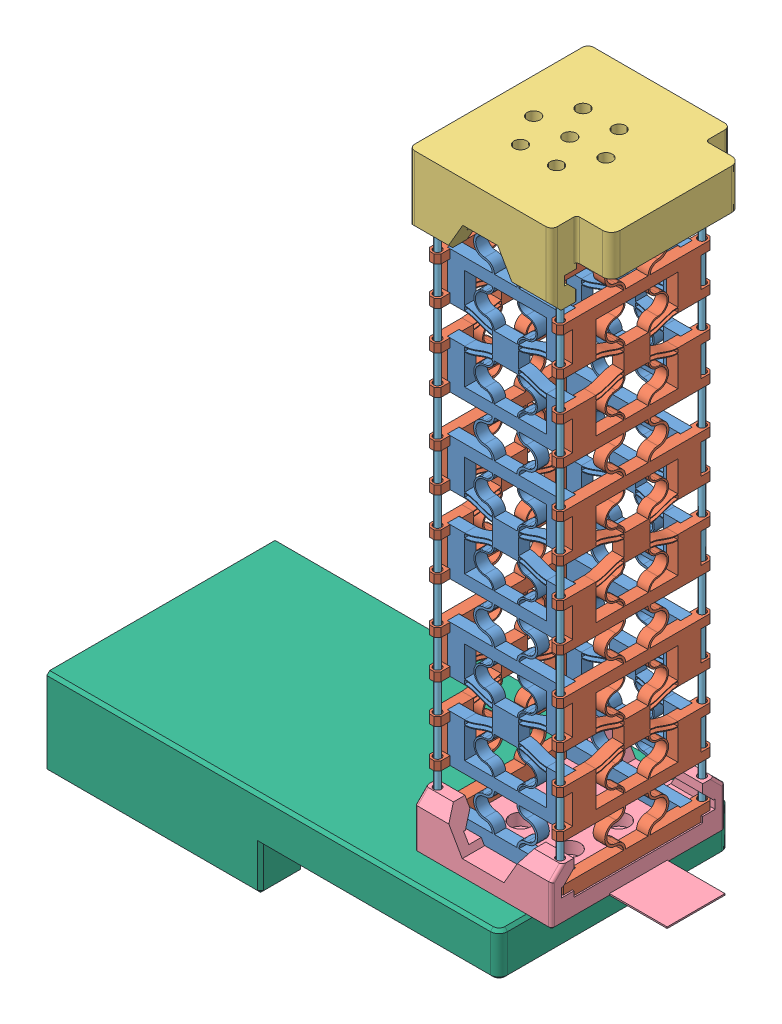
SolidWorks assembly Assem1, configuration Default. Lengths in mm.
Overall size (184.7 240.91 80).
11 component instances, 6 part files, 31 mates.
Components (placement in the parent):
- MM_ver1_of_ROC_ver8_FB-1: MM_ver1_of_ROC_ver8_FB [Default] at origin size (40.4 190.91 4)
- MM_ver1_of_ROC_ver8_LR-1: MM_ver1_of_ROC_ver8_LR [Default] at (-17 0 28.4) x (0 0 -1) z (1 0 0) size (53.1 190.91 4)
- MM_ver1_of_ROC_ver8_FB-2: MM_ver1_of_ROC_ver8_FB [Default] at (0 0 40.4) size (40.4 190.91 4)
- MM_ver1_of_ROC_ver8_LR-3: MM_ver1_of_ROC_ver8_LR [Default] at (29.4 0 16) x (0 0 1) z (-1 0 0) size (53.1 190.91 4)
- podstavek-1: podstavek [Default] at (29.4 57.9704 22.2) x (0 0 1) z (1 0 0) size (62 25.75 61.4)
- pokrov-1: pokrov [Default] at (29.4 -134.9408 22.2) x (0 0 -1) z (1 0 0) size (60 17.75 67.4)
- vodilo-1: vodilo [Default] at (-15 -138.0296 -2.35) x (0.99902 0 -0.044267) z (0.044267 0 0.99902) size (2 200 2)
- vodilo-2: vodilo [Default] at (27.4 -138.0296 -2.35) size (2 200 2)
- vodilo-3: vodilo [Default] at (-15 -138.0296 46.75) size (2 200 2)
- vodilo-4: vodilo [Default] at (27.4 -138.0296 46.75) size (2 200 2)
- drzalo-1: drzalo [Default] at (-86.8 -138.7408 62.2) x (0 -1 0) z (0 0 1) size (30 156.5 80)
Mates (geometry in assembly coordinates):
- Coincident5: coincident aligned: plane of MM_ver1_of_ROC_ver8_FB-1 through (0 56.9704 -40.7082) normal (0 1 0); plane of MM_ver1_of_ROC_ver8_LR-1 through (-61.6806 56.9704 28.4) normal (0 1 0)
- Coincident6: coincident aligned: plane of MM_ver1_of_ROC_ver8_FB-1 through (0 0 0) normal (0 0 -1); plane of MM_ver1_of_ROC_ver8_LR-1 through (-13 34.9704 0) normal (0 0 -1)
- Coincident7: coincident anti-aligned: plane of MM_ver1_of_ROC_ver8_FB-1 through (-14 -128.9408 -40.7082) normal (-1 0 0); plane of MM_ver1_of_ROC_ver8_LR-1 through (-14 56.9704 4.1) normal (1 0 0)
- Coincident8: coincident aligned: plane of MM_ver1_of_ROC_ver8_LR-1 through (-61.6806 56.9704 28.4) normal (0 1 0); plane of MM_ver1_of_ROC_ver8_FB-2 through (0 56.9704 -0.3082) normal (0 1 0)
- Coincident9: coincident aligned: plane of MM_ver1_of_ROC_ver8_LR-1 through (-61.6806 0 44.4) normal (0 0 1); plane of MM_ver1_of_ROC_ver8_FB-2 through (0 0 44.4) normal (0 0 1)
- Coincident14: coincident anti-aligned: plane of MM_ver1_of_ROC_ver8_FB-2 through (26.4 -128.9408 -0.3082) normal (1 0 0); plane of MM_ver1_of_ROC_ver8_LR-3 through (26.4 56.9704 4.1) normal (-1 0 0)
- Coincident15: coincident aligned: plane of MM_ver1_of_ROC_ver8_FB-2 through (-14 -133.9408 -0.3082) normal (0 -1 0); plane of MM_ver1_of_ROC_ver8_LR-3 through (74.0806 -133.9408 0) normal (0 -1 0)
- Coincident16: coincident aligned: plane of MM_ver1_of_ROC_ver8_FB-2 through (0 0 44.4) normal (0 0 1); plane of MM_ver1_of_ROC_ver8_LR-3 through (74.0806 -128.9408 44.4) normal (0 0 1)
- Coincident17: coincident anti-aligned: plane of MM_ver1_of_ROC_ver8_LR-1 through (-14 56.9704 40.3) normal (1 0 0); plane of MM_ver1_of_ROC_ver8_FB-2 through (-14 -128.9408 -0.3082) normal (-1 0 0)
- Coincident18: coincident anti-aligned: plane of MM_ver1_of_ROC_ver8_LR-3 through (74.0806 56.9704 16) normal (0 1 0); plane of podstavek-1 through (-17 56.9704 44.5) normal (0 -1 0)
- Width3: width anti-aligned: plane of MM_ver1_of_ROC_ver8_LR-3 through (29.4 62.8799 16) normal (1 0 0); plane of MM_ver1_of_ROC_ver8_LR-1 through (-17 62.8799 28.4) normal (-1 0 0); plane of podstavek-1 through (-18.5 57.9704 22.2) normal (-1 0 0); plane of podstavek-1 through (30.9 57.9704 22.2) normal (1 0 0)
- Width1: width anti-aligned: plane of MM_ver1_of_ROC_ver8_LR-3 through (74.0806 0 44.4) normal (0 0 1); plane of MM_ver1_of_ROC_ver8_LR-3 through (74.0806 0 0) normal (0 0 -1); plane of podstavek-1 through (-17 53.0204 44.5) normal (0 0 -1); plane of podstavek-1 through (-17 53.0204 -0.1) normal (0 0 1)
- Width4: width anti-aligned: plane of pokrov-1 through (-17.5 -134.9408 22.2) normal (-1 0 0); plane of pokrov-1 through (29.9 -134.9408 22.2) normal (1 0 0); plane of MM_ver1_of_ROC_ver8_LR-3 through (29.4 62.8799 16) normal (1 0 0); plane of MM_ver1_of_ROC_ver8_LR-1 through (-17 62.8799 28.4) normal (-1 0 0)
- Coincident22: coincident anti-aligned: plane of MM_ver1_of_ROC_ver8_LR-1 through (-61.6806 -133.9408 44.4) normal (0 -1 0); plane of pokrov-1 through (-17 -133.9408 -0.1) normal (0 1 0)
- Width2: width anti-aligned: plane of MM_ver1_of_ROC_ver8_FB-1 through (0 0 0) normal (0 0 -1); plane of MM_ver1_of_ROC_ver8_FB-2 through (0 0 44.4) normal (0 0 1); plane of pokrov-1 through (-17 -129.9908 -0.1) normal (0 0 1); plane of pokrov-1 through (-17 -129.9908 44.5) normal (0 0 -1)
- Coincident23: coincident anti-aligned: plane of podstavek-1 through (-17 61.9704 44.5) normal (0 -1 0); plane of vodilo-1 through (-15 61.9704 -2.35) normal (0 1 0)
- Concentric1: concentric aligned: cylinder of vodilo-1 through (-15 61.9704 -2.35) axis (0 -1 0) radius 1; cylinder of MM_ver1_of_ROC_ver8_LR-1 through (-15 -93.7713 -2.35) axis (0 -1 0) radius 1.35
- Coincident24: coincident aligned: plane of vodilo-2 through (27.4 -138.0296 -2.35) normal (0 -1 0); plane of vodilo-1 through (-15 -138.0296 -2.35) normal (0 -1 0)
- Concentric2: concentric aligned: cylinder of vodilo-2 through (27.4 61.9704 -2.35) axis (0 -1 0) radius 1; cylinder of MM_ver1_of_ROC_ver8_LR-3 through (27.4 -93.7713 -2.35) axis (0 -1 0) radius 1.35
- Concentric3: concentric aligned: cylinder of vodilo-4 through (27.4 61.9704 46.75) axis (0 -1 0) radius 1; cylinder of MM_ver1_of_ROC_ver8_LR-3 through (27.4 -93.7713 46.75) axis (0 -1 0) radius 1.35
- Concentric4: concentric aligned: cylinder of vodilo-3 through (-15 61.9704 46.75) axis (0 -1 0) radius 1; cylinder of MM_ver1_of_ROC_ver8_LR-1 through (-15 -93.7713 46.75) axis (0 -1 0) radius 1.35
- Coincident25: coincident aligned: plane of vodilo-1 through (-15 -138.0296 -2.35) normal (0 -1 0); plane of vodilo-3 through (-15 -138.0296 46.75) normal (0 -1 0)
- Coincident26: coincident aligned: plane of vodilo-1 through (-15 -138.0296 -2.35) normal (0 -1 0); plane of vodilo-4 through (27.4 -138.0296 46.75) normal (0 -1 0)
- Concentric5: concentric anti-aligned: cylinder of podstavek-1 through (-33.8 50.9704 -12.3) axis (1 0 0) radius 2; cylinder of wheel-1 through (8.7 50.9704 -12.3) axis (-1 0 0) radius 2.1
- Width5: width anti-aligned: plane of podstavek-1 through (9.2 44.9704 -16.3) normal (-1 0 0); plane of wheel-1 through (3.2 44.9704 -16.3) normal (1 0 0); plane of podstavek-1 through (8.7 50.9704 -12.3) normal (1 0 0); plane of wheel-1 through (3.7 50.9704 -12.3) normal (-1 0 0)
- Coincident27: coincident anti-aligned: plane of podstavek-1 through (46.2 60.9704 -17.8) normal (1 0 0); plane of Vital-1/Base-1 through (70.2 50.9704 22.2) normal (-1 0 0)
- Distance1: distance = 2 mm aligned: plane of podstavek-1 through (29.4 70.9704 22.2) normal (0 1 0); plane of Vital-1/Base-1 through (100.2 64.9704 22.2) normal (0 1 0)
- Width7: width aligned: plane of Vital-1/Base-1 through (100.2 58.6763 5.0782) normal (0 0.410411 -0.911901); plane of podstavek-1 through (100.2 58.6763 39.3218) normal (0 0.410411 0.911901); plane of Vital-1/Base-1 through (46.2 60.9704 62.2) normal (0 0 1); plane of podstavek-1 through (46.2 60.9704 -17.8) normal (0 0 -1)
- Coincident28: coincident anti-aligned: plane of pokrov-1 through (-17 -139.9408 22.2) normal (0 -1 0); plane of drzalo-1 through (-6.3 -139.9408 72.2) normal (0 1 0)
- Concentric6: concentric anti-aligned: circle of pokrov-1; cylinder of drzalo-1 through (14.7 -151.1408 13.7) axis (0 1 0) radius 3.6
- Concentric9: concentric aligned: circle of pokrov-1; circle of drzalo_leva_srednja-1
